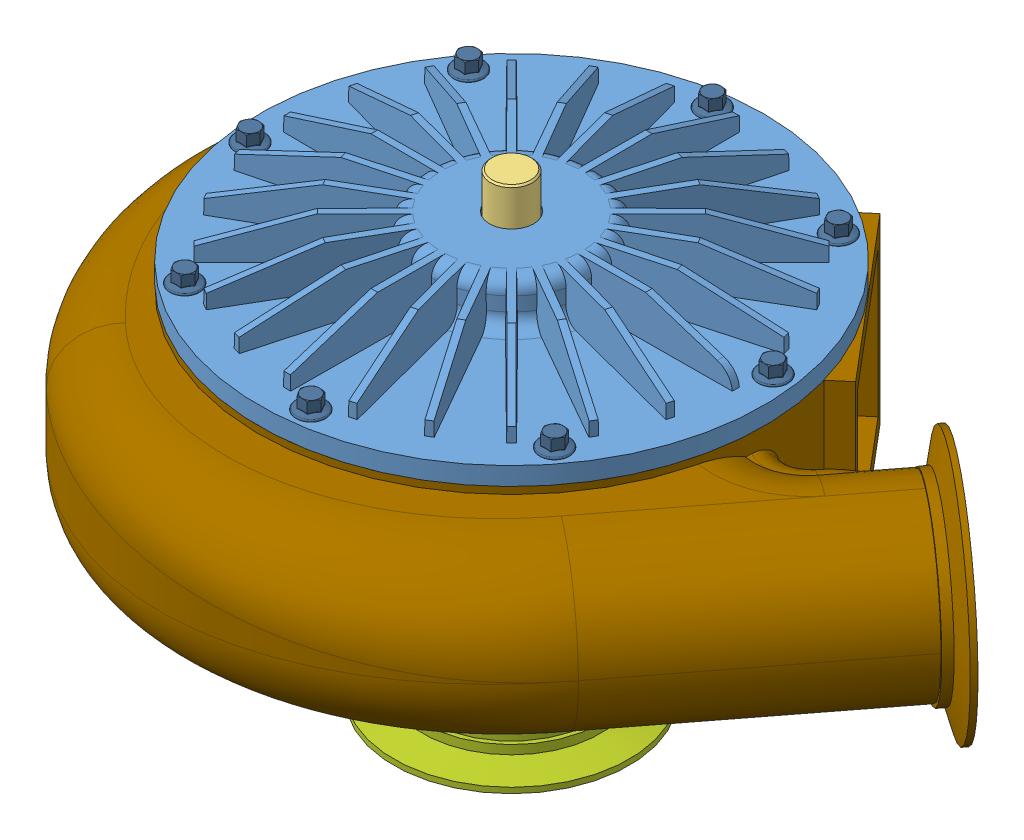
SolidWorks assembly Assem2, configuration Défaut. Lengths in mm.
Overall size (411.32 207.3 406.49).
35 component instances, 10 part files, 44 mates.
Components (placement in the parent):
- part05-1: part05 [Défaut] at origin size (228.5 35.71 228.5)
- angular contact ball bearing_68_iso-4: angular contact ball bearing_68_iso [ISO 15 ABB - 3310 - Full,DE,AC,Full_68] at (0 15.85 0) x (0 -1 0) z (0.056535 0 0.998401) size (19 35 35)
- Assem1-1: Assem1 [Défaut] at (-33.6957 16.5291 -73.5907) x (0.97801 0 -0.208558) z (0.208558 0 0.97801) size (273.53 177.15 273.53)
  - PART01-1: PART01 [Défaut] at (17.6068 -35.425 79) size (79 70.85 79)
  - PART02-1: PART02 [Défaut] at (17.6068 -34.425 79) x (0.863759 0 -0.503906) z (0 -1 0) size (200 200 2)
  - PART03-2: PART03 [Défaut] at (17.6068 -40.24 79) x (1 0 0) z (0 -1 0) size (69.88 69.88 9.63)
  - PART03-3: PART03 [Défaut] at (17.6068 -49.87 79) x (1 0 0) z (0 -1 0) size (69.88 69.88 9.63)
  - PART03-4: PART03 [Défaut] at (17.6068 -59.5 79) x (1 0 0) z (0 -1 0) size (69.88 69.88 9.63)
  - PART03-5: PART03 [Défaut] at (17.6068 -69.13 79) x (1 0 0) z (0 -1 0) size (69.88 69.88 9.63)
  - PART03-6: PART03 [Défaut] at (17.6068 -78.76 79) x (1 0 0) z (0 -1 0) size (69.88 69.88 9.63)
  - PART02-2: PART02 [Défaut] at (17.6068 -44.055 79) x (0.863759 0 -0.503906) z (0 -1 0) size (200 200 2)
  - PART02-3: PART02 [Défaut] at (17.6068 -53.685 79) x (0.863759 0 -0.503906) z (0 -1 0) size (200 200 2)
  - PART02-4: PART02 [Défaut] at (17.6068 -63.315 79) x (0.863759 0 -0.503906) z (0 -1 0) size (200 200 2)
  - PART02-5: PART02 [Défaut] at (17.6068 -72.945 79) x (0.863759 0 -0.503906) z (0 -1 0) size (200 200 2)
  - PART02-6: PART02 [Défaut] at (17.6068 -82.575 79) x (0.92388 0 0.382682) z (0 -1 0) size (200 200 2)
  - PART04-1: PART04 [Défaut] at (17.6068 -83.575 79) x (-0.239212 0 0.970967) z (0.970967 0 0.239212) size (82.7 58.15 82.7)
- part06-1: part06 [Défaut] at (0 -64.8 0) x (-0.965926 0 0.258819) z (0.258819 0 0.965926) size (228.5 90.55 228.5)
- thrust roller bearing_iso-1: thrust roller bearing_iso [ISO 104 - 7370125 - R,16,SI,NC,16] at (0 -77.7 0) x (0 1 0) z (-0.496619 0 -0.867969) size (25 125 125)
- part07-1: part07 [Défaut] at (0 -33.025 0) x (0 -1 0) z (-0.609447 0 0.792826) size (104 304.76 278.44)
- hex flange bolt small_iso-2: hex flange bolt small_iso [ISO 4162 - M6 x 16 x 16-S] at (104.5974 23.15 -13.7705) x (0 -1 0) z (-0.049119 0 0.998793) size (22.8 13.6 13.6)
- hex flange bolt small_iso-3: hex flange bolt small_iso [ISO 4162 - M6 x 16 x 16-S] at (83.6988 23.15 64.2243) x (0 -1 0) z (0 0 1) size (22.8 13.6 13.6)
- hex flange bolt small_iso-4: hex flange bolt small_iso [ISO 4162 - M6 x 16 x 16-S] at (64.2243 23.15 -83.6988) x (0 -1 0) z (0 0 1) size (22.8 13.6 13.6)
- hex flange bolt small_iso-5: hex flange bolt small_iso [ISO 4162 - M6 x 16 x 16-S] at (-13.7705 23.15 -104.5974) x (0 -1 0) z (0 0 1) size (22.8 13.6 13.6)
- hex flange bolt small_iso-6: hex flange bolt small_iso [ISO 4162 - M6 x 16 x 16-S] at (-83.6988 23.15 -64.2243) x (0 -1 0) z (0 0 1) size (22.8 13.6 13.6)
- hex flange bolt small_iso-7: hex flange bolt small_iso [ISO 4162 - M6 x 16 x 16-S] at (-104.5974 23.15 13.7705) x (0 -1 0) z (0 0 1) size (22.8 13.6 13.6)
- hex flange bolt small_iso-8: hex flange bolt small_iso [ISO 4162 - M6 x 16 x 16-S] at (-64.2243 23.15 83.6988) x (0 -1 0) z (0 0 1) size (22.8 13.6 13.6)
- hex flange bolt small_iso-9: hex flange bolt small_iso [ISO 4162 - M6 x 16 x 16-S] at (13.7705 23.15 104.5974) x (0 -1 0) z (0 0 1) size (22.8 13.6 13.6)
- hex flange bolt small_iso-10: hex flange bolt small_iso [ISO 4162 - M6 x 16 x 16-S] at (13.7705 -90.45 104.5974) x (0 1 0) z (0 0 1) size (22.8 13.6 13.6)
- hex flange bolt small_iso-11: hex flange bolt small_iso [ISO 4162 - M6 x 16 x 16-S] at (83.6988 -90.45 64.2243) x (0 1 0) z (0 0 1) size (22.8 13.6 13.6)
- hex flange bolt small_iso-12: hex flange bolt small_iso [ISO 4162 - M6 x 16 x 16-S] at (104.5974 -90.45 -13.7705) x (0 1 0) z (0 0 1) size (22.8 13.6 13.6)
- hex flange bolt small_iso-13: hex flange bolt small_iso [ISO 4162 - M6 x 16 x 16-S] at (64.2243 -90.45 -83.6988) x (0 1 0) z (0 0 1) size (22.8 13.6 13.6)
- hex flange bolt small_iso-14: hex flange bolt small_iso [ISO 4162 - M6 x 16 x 16-S] at (-13.7705 -90.45 -104.5974) x (0 1 0) z (0 0 1) size (22.8 13.6 13.6)
- hex flange bolt small_iso-15: hex flange bolt small_iso [ISO 4162 - M6 x 16 x 16-S] at (-83.6988 -90.45 -64.2243) x (0 1 0) z (0 0 1) size (22.8 13.6 13.6)
- hex flange bolt small_iso-16: hex flange bolt small_iso [ISO 4162 - M6 x 16 x 16-S] at (-104.5974 -90.45 13.7705) x (0 1 0) z (0 0 1) size (22.8 13.6 13.6)
- hex flange bolt small_iso-17: hex flange bolt small_iso [ISO 4162 - M6 x 16 x 16-S] at (-64.2243 -90.45 83.6988) x (0 1 0) z (0 0 1) size (22.8 13.6 13.6)
Mates (geometry in assembly coordinates):
- Concentric3: concentric aligned: cylinder of part05-1 through (0 0 0) axis (0 -1 0) radius 16.88; cylinder of angular contact ball bearing_68_iso-4 through (0 36.4875 0) axis (0 -1 0) radius 5
- Coincident1: coincident anti-aligned: plane of part05-1 through (0 25.35 16.88) normal (0 -1 0); plane of angular contact ball bearing_68_iso-4 through (14.951 25.35 -0.8466) normal (0 1 0)
- Concentric4: concentric aligned: cylinder of part05-1 through (0 0 0) axis (0 -1 0) radius 10; cylinder of Assem1-1/PART01-1 through (0 -18.8959 0) axis (0 -1 0) radius 9.5
- Concentric5: concentric aligned: cylinder of part06-1 through (0 -90.2 0) axis (0 1 0) radius 62.25; cylinder of thrust roller bearing_iso-1 through (0 -112.625 0) axis (0 1 0) radius 35
- Concentric6: concentric anti-aligned: cylinder of part06-1 through (0 -64.8 0) axis (0 -1 0) radius 35; cylinder of thrust roller bearing_iso-1 through (0 -112.625 0) axis (0 1 0) radius 35
- Coincident2: coincident anti-aligned: plane of part06-1 through (0 -90.2 0) normal (0 1 0); plane of thrust roller bearing_iso-1 through (31.3337 -90.2 -17.9279) normal (0 -1 0)
- Concentric12: concentric anti-aligned: cylinder of Assem1-1/PART04-1 through (0 -67.0459 0) axis (0 1 0) radius 35; cylinder of part06-1 through (0 -64.8 0) axis (0 -1 0) radius 35
- Concentric14: concentric aligned: cylinder of part06-1 through (0 -155.35 0) axis (0 1 0) radius 38.25; cylinder of part07-1 through (0 -71.025 0) axis (0 1 0) radius 101.5
- Coincident4: coincident anti-aligned: plane of part05-1 through (0 8.175 114.25) normal (0 -1 0); plane of part07-1 through (0 8.175 0) normal (0 1 0)
- Concentric16: concentric aligned: cylinder of part05-1 through (83.6988 0 64.2243) axis (0 1 0) radius 3.5; cylinder of part07-1 through (83.6988 8.175 64.2243) axis (0 1 0) radius 2.7051
- Coincident5: coincident anti-aligned: plane of part06-1 through (29.5701 -74.225 110.357) normal (0 1 0); plane of part07-1 through (0 -74.225 0) normal (0 -1 0)
- Concentric17: concentric aligned: cylinder of part06-1 through (83.6988 -64.8 64.2243) axis (0 -1 0) radius 3.5; cylinder of part07-1 through (83.6988 -74.225 64.2243) axis (0 -1 0) radius 2.7051
- Concentric18: concentric aligned: cylinder of part05-1 through (104.5974 0 -13.7705) axis (0 1 0) radius 3.5; cylinder of hex flange bolt small_iso-2 through (104.5974 23.15 -13.7705) axis (0 1 0) radius 3
- Concentric19: concentric aligned: cylinder of part05-1 through (83.6988 0 64.2243) axis (0 1 0) radius 3.5; cylinder of hex flange bolt small_iso-3 through (83.6988 23.15 64.2243) axis (0 1 0) radius 3
- Coincident7: coincident anti-aligned: plane of part05-1 through (0 16.35 38) normal (0 1 0); plane of hex flange bolt small_iso-3 through (88.3176 16.35 64.2243) normal (0 -1 0)
- Concentric20: concentric aligned: cylinder of part05-1 through (64.2243 0 -83.6988) axis (0 1 0) radius 3.5; cylinder of hex flange bolt small_iso-4 through (64.2243 23.15 -83.6988) axis (0 1 0) radius 3
- Coincident8: coincident anti-aligned: plane of part05-1 through (0 16.35 38) normal (0 1 0); plane of hex flange bolt small_iso-4 through (68.8431 16.35 -83.6988) normal (0 -1 0)
- Concentric21: concentric aligned: cylinder of part05-1 through (-13.7705 0 -104.5974) axis (0 1 0) radius 3.5; cylinder of hex flange bolt small_iso-5 through (-13.7705 23.15 -104.5974) axis (0 1 0) radius 3
- Coincident9: coincident anti-aligned: plane of part05-1 through (0 16.35 38) normal (0 1 0); plane of hex flange bolt small_iso-5 through (-9.1517 16.35 -104.5974) normal (0 -1 0)
- Concentric22: concentric aligned: cylinder of part05-1 through (-83.6988 0 -64.2243) axis (0 1 0) radius 3.5; cylinder of hex flange bolt small_iso-6 through (-83.6988 23.15 -64.2243) axis (0 1 0) radius 3
- Coincident10: coincident anti-aligned: plane of part05-1 through (0 16.35 38) normal (0 1 0); plane of hex flange bolt small_iso-6 through (-79.08 16.35 -64.2243) normal (0 -1 0)
- Concentric23: concentric aligned: cylinder of part05-1 through (-104.5974 0 13.7705) axis (0 1 0) radius 3.5; cylinder of hex flange bolt small_iso-7 through (-104.5974 23.15 13.7705) axis (0 1 0) radius 3
- Coincident11: coincident anti-aligned: plane of part05-1 through (0 16.35 38) normal (0 1 0); plane of hex flange bolt small_iso-7 through (-99.9786 16.35 13.7705) normal (0 -1 0)
- Concentric24: concentric aligned: cylinder of part05-1 through (-64.2243 0 83.6988) axis (0 1 0) radius 3.5; cylinder of hex flange bolt small_iso-8 through (-64.2243 23.15 83.6988) axis (0 1 0) radius 3
- Coincident12: coincident anti-aligned: plane of part05-1 through (0 16.35 38) normal (0 1 0); plane of hex flange bolt small_iso-8 through (-59.6055 16.35 83.6988) normal (0 -1 0)
- Concentric25: concentric aligned: cylinder of part05-1 through (13.7705 0 104.5974) axis (0 1 0) radius 3.5; cylinder of hex flange bolt small_iso-9 through (13.7705 23.15 104.5974) axis (0 1 0) radius 3
- Coincident13: coincident anti-aligned: plane of part05-1 through (0 16.35 38) normal (0 1 0); plane of hex flange bolt small_iso-9 through (18.3893 16.35 104.5974) normal (0 -1 0)
- Concentric26: concentric aligned: cylinder of part06-1 through (13.7705 -64.8 104.5974) axis (0 -1 0) radius 3.5; cylinder of hex flange bolt small_iso-10 through (13.7705 -90.45 104.5974) axis (0 -1 0) radius 3
- Coincident14: coincident anti-aligned: plane of part06-1 through (18.182 -83.65 67.8563) normal (0 -1 0); plane of hex flange bolt small_iso-10 through (9.1517 -83.65 104.5974) normal (0 1 0)
- Concentric27: concentric aligned: cylinder of part06-1 through (83.6988 -64.8 64.2243) axis (0 -1 0) radius 3.5; cylinder of hex flange bolt small_iso-11 through (83.6988 -90.45 64.2243) axis (0 -1 0) radius 3
- Coincident15: coincident anti-aligned: plane of part06-1 through (18.182 -83.65 67.8563) normal (0 -1 0); plane of hex flange bolt small_iso-11 through (79.08 -83.65 64.2243) normal (0 1 0)
- Concentric28: concentric aligned: cylinder of part06-1 through (104.5974 -64.8 -13.7705) axis (0 -1 0) radius 3.5; cylinder of hex flange bolt small_iso-12 through (104.5974 -90.45 -13.7705) axis (0 -1 0) radius 3
- Coincident16: coincident anti-aligned: plane of part06-1 through (18.182 -83.65 67.8563) normal (0 -1 0); plane of hex flange bolt small_iso-12 through (99.9786 -83.65 -13.7705) normal (0 1 0)
- Concentric29: concentric aligned: cylinder of part06-1 through (64.2243 -64.8 -83.6988) axis (0 -1 0) radius 3.5; cylinder of hex flange bolt small_iso-13 through (64.2243 -90.45 -83.6988) axis (0 -1 0) radius 3
- Coincident17: coincident anti-aligned: plane of part06-1 through (18.182 -83.65 67.8563) normal (0 -1 0); plane of hex flange bolt small_iso-13 through (59.6055 -83.65 -83.6988) normal (0 1 0)
- Concentric30: concentric aligned: cylinder of part06-1 through (-13.7705 -64.8 -104.5974) axis (0 -1 0) radius 3.5; cylinder of hex flange bolt small_iso-14 through (-13.7705 -90.45 -104.5974) axis (0 -1 0) radius 3
- Coincident18: coincident anti-aligned: plane of part06-1 through (18.182 -83.65 67.8563) normal (0 -1 0); plane of hex flange bolt small_iso-14 through (-18.3893 -83.65 -104.5974) normal (0 1 0)
- Concentric31: concentric aligned: cylinder of part06-1 through (-83.6988 -64.8 -64.2243) axis (0 -1 0) radius 3.5; cylinder of hex flange bolt small_iso-15 through (-83.6988 -90.45 -64.2243) axis (0 -1 0) radius 3
- Coincident19: coincident anti-aligned: plane of part06-1 through (18.182 -83.65 67.8563) normal (0 -1 0); plane of hex flange bolt small_iso-15 through (-88.3176 -83.65 -64.2243) normal (0 1 0)
- Concentric32: concentric aligned: cylinder of part06-1 through (-104.5974 -64.8 13.7705) axis (0 -1 0) radius 3.5; cylinder of hex flange bolt small_iso-16 through (-104.5974 -90.45 13.7705) axis (0 -1 0) radius 3
- Coincident20: coincident anti-aligned: plane of part06-1 through (18.182 -83.65 67.8563) normal (0 -1 0); plane of hex flange bolt small_iso-16 through (-109.2162 -83.65 13.7705) normal (0 1 0)
- Concentric33: concentric aligned: cylinder of part06-1 through (-64.2243 -64.8 83.6988) axis (0 -1 0) radius 3.5; cylinder of hex flange bolt small_iso-17 through (-64.2243 -90.45 83.6988) axis (0 -1 0) radius 3
- Coincident21: coincident anti-aligned: plane of part06-1 through (18.182 -83.65 67.8563) normal (0 -1 0); plane of hex flange bolt small_iso-17 through (-68.8431 -83.65 83.6988) normal (0 1 0)
- Coincident22: coincident anti-aligned: plane of part05-1 through (0 16.35 38) normal (0 1 0); plane of hex flange bolt small_iso-2 through (109.2107 16.35 -13.5436) normal (0 -1 0)
